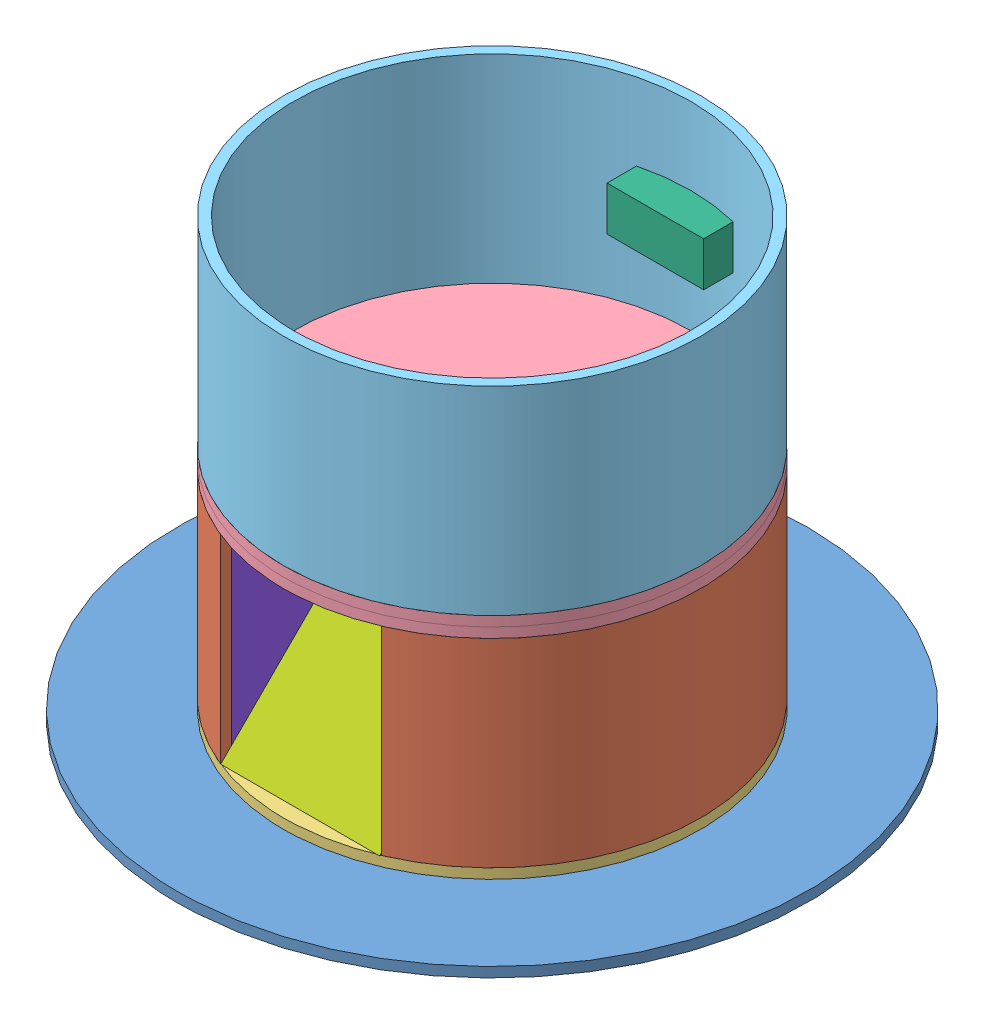
SolidWorks assembly CandyDispenser, configuration Default. Lengths in mm.
Overall size (317.5 220 317.5).
11 component instances, 9 part files, 20 mates.
Components (placement in the parent):
- TurtlebotBase-1: TurtlebotBase [Default] at (-430.4689 448.1676 86.1198) size (317.5 5 317.5)
- DispenserPart1-1: DispenserPart1 [Default] at (-430.4689 458.1676 86.1198) size (210 100 202.36)
- DispenserPart3-3: DispenserPart3 [Default] at (-430.4689 453.1676 86.1198) size (210 5 210)
- DispenserPart4-1: DispenserPart4 [Default] at (-430.4689 558.1676 86.1198) size (210 5 210)
- DispenserPart4-2: DispenserPart4 [Default] at (-430.4689 563.1676 86.1198) size (210 5 210)
- DispenserPart2-1: DispenserPart2 [Default] at (-430.4689 568.1676 86.1198) size (210 100 210)
- IRSensor-1: IRSensor [Default] at (-430.4685 618.1656 -16.0272) size (48.62 22.26 20)
- DispenserPart5-2: DispenserPart5 [Default] at (-389.7995 458.1676 78.4754) x (0 0 1) z (-1 0 0) size (105 100 80)
- DispenserPart6-4: DispenserPart6 [Default] at (-384.4391 558.1676 177.315) x (0 0 -1) z (-1 0 0) size (100 100 5)
- DispenserPart6-5: DispenserPart6 [Default] at (-469.7995 558.1676 178.0606) x (0 0 -1) z (-1 0 0) size (100 100 5)
- ServoMotor-1: ServoMotor [Default] at (-417.949 547.0376 58.4754) size (49.74 27.83 23.39)
Mates (geometry in assembly coordinates):
- Coincident10: coincident anti-aligned: plane of DispenserPart1-1 through (-430.4689 558.1676 86.1198) normal (0 1 0); plane of DispenserPart4-1 through (-430.4689 558.1676 86.1198) normal (0 -1 0)
- Concentric3: concentric aligned: circle of DispenserPart1-1; circle of DispenserPart4-1
- Concentric4: concentric aligned: circle of DispenserPart3-3; circle of DispenserPart4-1
- Coincident14: coincident anti-aligned: plane of TurtlebotBase-1 through (-430.4689 453.1676 86.1198) normal (0 1 0); plane of DispenserPart3-3 through (-430.4689 453.1676 86.1198) normal (0 -1 0)
- Coincident15: coincident anti-aligned: plane of DispenserPart1-1 through (-430.4689 458.1676 86.1198) normal (0 -1 0); plane of DispenserPart3-3 through (-430.4689 458.1676 86.1198) normal (0 1 0)
- Concentric5: concentric aligned: circle of DispenserPart4-1; circle of DispenserPart4-2
- Coincident17: coincident anti-aligned: plane of DispenserPart4-1 through (-430.4689 563.1676 86.1198) normal (0 1 0); plane of DispenserPart4-2 through (-430.4689 563.1676 86.1198) normal (0 -1 0)
- Concentric7: concentric aligned: circle of DispenserPart4-2; circle of DispenserPart2-1
- Coincident21: coincident anti-aligned: plane of DispenserPart4-2 through (-430.4689 568.1676 86.1198) normal (0 1 0); plane of DispenserPart2-1 through (-430.4689 568.1676 86.1198) normal (0 -1 0)
- Concentric8: concentric aligned: circle of TurtlebotBase-1; circle of DispenserPart3-3
- Coincident34: coincident aligned: line of DispenserPart2-1 through (-406.1585 607.0396 -16.0272) axis (0 1 0); line of IRSensor-1 through (-406.1585 607.0356 -16.0272) axis (0 1 0)
- Coincident35: coincident anti-aligned: plane of DispenserPart2-1 through (-406.1585 629.2956 -100.8802) normal (0 -1 0); plane of IRSensor-1 through (-454.7785 629.2956 3.9728) normal (0 1 0)
- Coincident49: coincident anti-aligned: line of DispenserPart1-1 through (-469.7995 458.1676 183.4754) axis (0 0 -1); line of DispenserPart5-2 through (-469.7995 458.1676 178.4754) axis (0 0 1)
- Coincident50: coincident: point of DispenserPart1-1; point of DispenserPart5-2
- Coincident53: coincident anti-aligned: plane of DispenserPart4-1 through (-430.4689 558.1676 86.1198) normal (0 -1 0); plane of DispenserPart6-4 through (-389.4391 558.1676 77.315) normal (0 1 0)
- Coincident54: coincident anti-aligned: line of DispenserPart1-1 through (-389.4391 558.1676 177.315) axis (0 -1 0); line of DispenserPart6-4 through (-389.4391 458.1676 177.315) axis (0 1 0)
- Parallel10: parallel anti-aligned: line of DispenserPart5-2 through (-389.7995 458.1676 183.4754) axis (0 0.707107 -0.707107); line of DispenserPart6-4 through (-389.4391 558.1676 77.315) axis (0 -0.707107 0.707107)
- Coincident64: coincident anti-aligned: line of DispenserPart1-1 through (-469.7995 558.1676 178.0606) axis (0 -1 0); line of DispenserPart6-5 through (-469.7995 458.1676 178.0606) axis (0 1 0)
- Coincident65: coincident: plane of DispenserPart4-1 through (-430.4689 558.1676 86.1198) normal (0 -1 0); line of DispenserPart6-5 through (-469.7995 558.1676 178.0606) axis (0 0 -1)
- Coincident75: coincident aligned: line of DispenserPart5-2 through (-469.7995 558.1676 78.4754) axis (1 0 0); line of ServoMotor-1 through (-442.259 558.1676 78.4754) axis (1 0 0)
